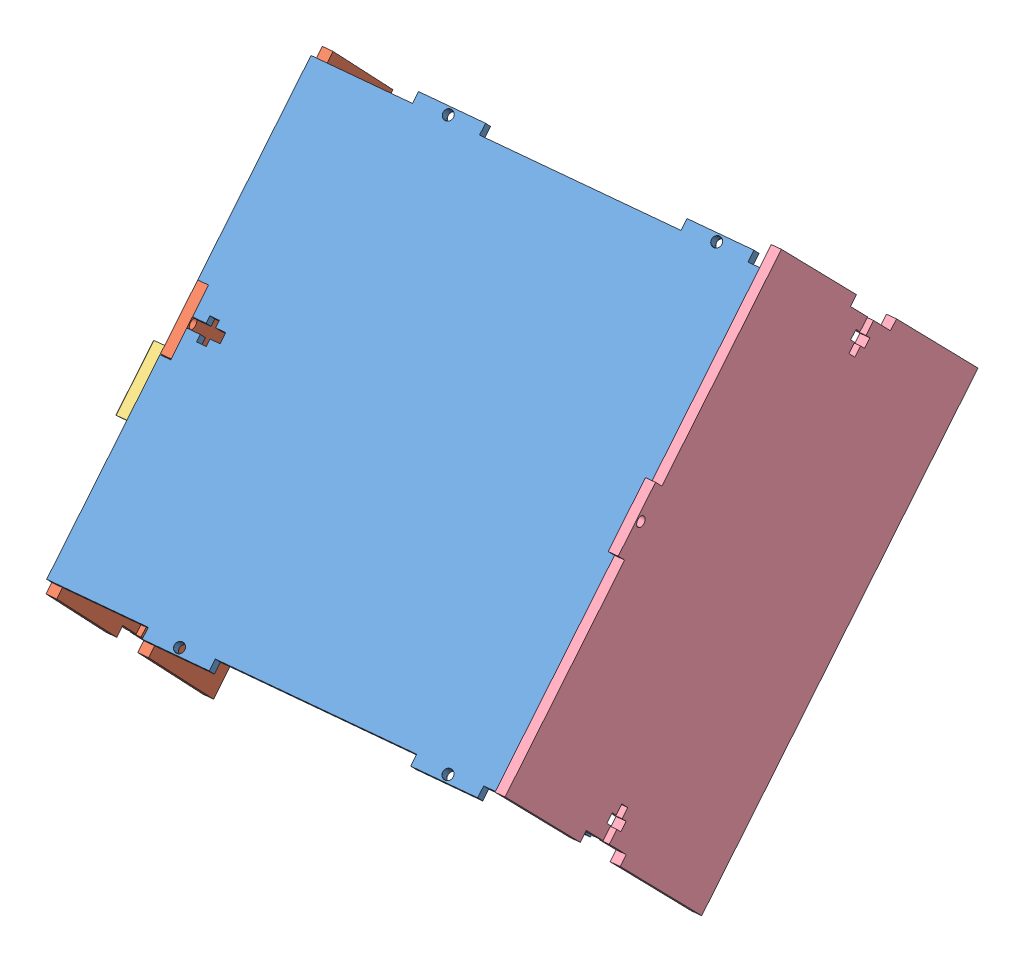
SolidWorks assembly prizewheelassembly xxx, configuration Default. Lengths in mm.
Overall size (199.77 204.4 185.85).
4 component instances, 4 part files, 7 mates.
Components (placement in the parent):
- prizewheel.floor-1: prizewheel.floor [Default] at (-47.6544 76.7843 90.5667) x (0.986116 -0.053682 -0.15714) z (0.147974 0.713497 0.684854) size (158.76 146.36 3.18)
- prizewheel.frontbackwall2-3: prizewheel.frontbackwall2 [Default] at (-132.9883 47.1561 70.3387) x (0.075354 -0.698599 0.711535) z (0.986116 -0.053682 -0.15714) size (146.36 101.6 3.18)
- 9V Battery Holder-1: 9V Battery Holder [Default] at (-130.8862 39.7529 86.0595) x (0.147974 0.713497 0.684854) z (-0.986116 0.053682 0.15714) size (53.5 30 19.31)
- prizewheel.frontbackwalls-1: prizewheel.frontbackwalls [Default] at (35.745 76.473 81.2531) x (0.075354 -0.698599 0.711535) z (0.996826 0.034403 -0.07179) size (146.36 101.6 3.18)
Mates (geometry in assembly coordinates):
- Coincident25: coincident aligned: line of prizewheel.floor-1 through (-125.1788 74.0596 110.1558) axis (0.075354 -0.698599 0.711535); line of prizewheel.frontbackwall2-3 through (-125.1976 74.2342 109.9779) axis (0.075354 -0.698599 0.711535)
- Coincident26: coincident anti-aligned: plane of prizewheel.floor-1 through (-47.9374 86.0392 85.6292) normal (0.075354 -0.698599 0.711535); plane of prizewheel.frontbackwall2-3 through (-126.2153 90.3004 98.1029) normal (-0.075354 0.698599 -0.711535)
- Coincident45: coincident anti-aligned: plane of prizewheel.frontbackwall2-3 through (-132.9883 47.1561 70.3387) normal (-0.986116 0.053682 0.15714); plane of 9V Battery Holder-1 through (-130.8862 39.7529 86.0595) normal (0.986116 -0.053682 -0.15714)
- Coincident48: coincident anti-aligned: plane of prizewheel.floor-1 through (-47.6544 76.7843 90.5667) normal (-0.147974 -0.713497 -0.684854); plane of prizewheel.frontbackwall2-3 through (-131.4562 132.2563 50.8814) normal (0.147974 0.713497 0.684854)
- Parallel8: parallel: line of prizewheel.frontbackwall2-3 through (-126.6859 88.0315 95.9251) axis (-0.075354 0.698599 -0.711535); plane of 9V Battery Holder-1 through (-128.4536 51.977 111.8579) normal (-0.00811 0.713111 0.701005)
- Coincident54: coincident anti-aligned: plane of prizewheel.floor-1 through (-47.9374 86.0392 85.6292) normal (0.075354 -0.698599 0.711535); plane of prizewheel.frontbackwalls-1 through (36.3051 119.6777 109.7346) normal (-0.075354 0.698599 -0.711535)
- Coincident67: coincident anti-aligned: circle of prizewheel.frontbackwall2-3; cylinder of 9V Battery Holder-1 through (-133.9793 47.4218 78.7381) axis (-0.986116 0.053682 0.15714) radius 1.4
